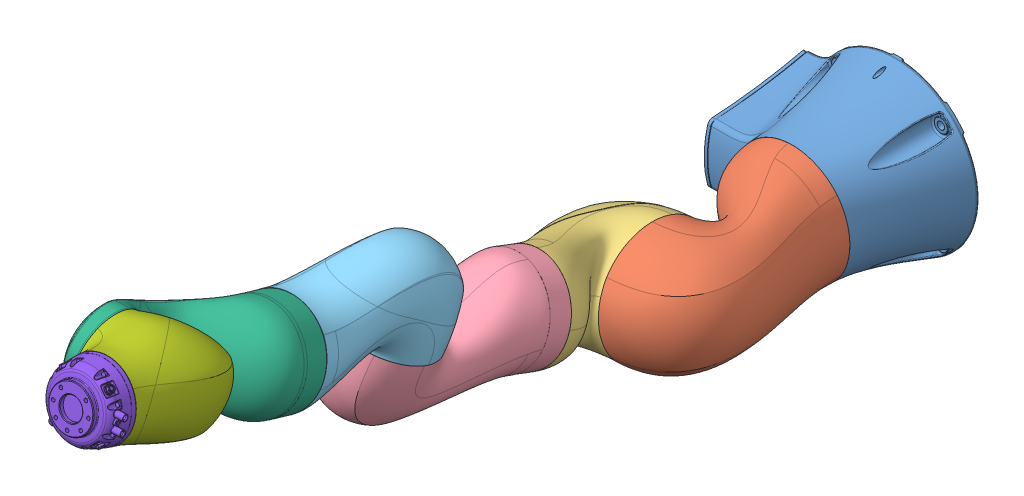
SolidWorks assembly Assembly_1, configuration Default. Lengths in mm.
Overall size (266.54 504.99 1268.37).
8 component instances, 8 part files, 15 mates.
Components (placement in the parent):
- Base_Linkv2-1: Base_Linkv2 [Default] at origin size (257.48 242.95 157.94)
- Link_1v2-1: Link_1v2 [Default] x (-0.064561 0.997914 0) z (0 0 1) size (182.55 209.04 299.35)
- Link_2-1: Link_2 [Default] at (8.0481 -124.3985 22.2717) x (-0.06054 0.935757 -0.34741) z (-0.022429 0.346685 0.937713) size (180.63 205.49 291.74)
- Link_3-1: Link_3 [Default] at (8.0745 -124.8068 22.4232) x (-0.974112 0.203468 -0.098525) z (-0.022429 0.346685 0.937713) size (143.85 187.8 294.72)
- Link_4-1: Link_4 [Default] at (-61.5676 -109.1397 18.4592) x (-0.972074 0.234356 -0.012253) z (0.066856 0.3266 0.942795) size (143.87 187.74 254.27)
- Link_5-1: Link_5 [Default] at (-61.5676 -109.1397 18.4592) x (-0.175544 -0.92632 0.33334) z (0.066856 0.3266 0.942795) size (137.43 170.87 294.55)
- Link_6-1: Link_6 [Default] at (-40.3008 2.9254 -15.504) x (-0.181385 -0.954507 0.236676) z (0.048833 0.231629 0.971578) size (143.46 137.97 168.89)
- Link_8-1: Link_8 [Default] at (-40.3008 2.9254 -15.504) x (0.011265 -0.972804 0.231355) z (0.048833 0.231629 0.971578) size (103.89 109.94 54.9)
Mates (geometry in assembly coordinates):
- Coincident1: coincident anti-aligned: plane of Base_Linkv2-1 through (0 0 147.5) normal (0 0 1); plane of Link_1v2-1 through (0 0 147.5) normal (0 0 -1)
- Concentric1: concentric anti-aligned: cylinder of Base_Linkv2-1 through (0 0 157.5) axis (0 0 1) radius 25; cylinder of Link_1v2-1 through (0 0 157.5) axis (0 0 -1) radius 25
- Coincident2: coincident anti-aligned: plane of Link_1v2-1 through (0 0 335) normal (-0.997914 -0.064561 0); plane of Link_2-1 through (1.8504 -28.6016 282.6387) normal (0.997914 0.064561 0)
- Concentric2: concentric anti-aligned: cylinder of Link_1v2-1 through (0 0 360) axis (-0.997914 -0.064561 0) radius 25; cylinder of Link_2-1 through (0 0 360) axis (0.997914 0.064561 0) radius 25
- Coincident3: coincident anti-aligned: plane of Link_2-1 through (-68.4533 66.7653 551.7624) normal (-0.022429 0.346685 0.937713); plane of Link_3-1 through (-4.5868 70.8972 551.7624) normal (0.022429 -0.346685 -0.937713)
- Concentric3: concentric anti-aligned: cylinder of Link_2-1 through (-4.5868 70.8972 551.7624) axis (-0.022429 0.346685 0.937713) radius 25; cylinder of Link_3-1 through (-4.5868 70.8972 551.7624) axis (0.022429 -0.346685 -0.937713) radius 25
- Coincident4: coincident anti-aligned: plane of Link_3-1 through (-11.7823 135.9936 757.3376) normal (0.224951 0.915647 -0.333147); plane of Link_4-1 through (-11.7823 135.9936 757.3376) normal (-0.224951 -0.915647 0.333147)
- Concentric4: concentric anti-aligned: cylinder of Link_3-1 through (-9.5328 145.1501 754.0061) axis (0.224951 0.915647 -0.333147) radius 25; cylinder of Link_4-1 through (-9.5328 145.1501 754.0061) axis (-0.224951 -0.915647 0.333147) radius 25
- Coincident5: coincident anti-aligned: plane of Link_4-1 through (2.246 202.5995 918.3574) normal (0.066856 0.3266 0.942795); plane of Link_5-1 through (2.246 202.5995 918.3574) normal (-0.066856 -0.3266 -0.942795)
- Concentric5: concentric anti-aligned: cylinder of Link_4-1 through (2.9146 205.8655 927.7853) axis (0.066856 0.3266 0.942795) radius 25; cylinder of Link_5-1 through (2.9146 205.8655 927.7853) axis (-0.066856 -0.3266 -0.942795) radius 25
- Coincident6: coincident anti-aligned: plane of Link_5-1 through (-52.1195 289.5243 1131.2827) normal (0.982199 -0.187787 -0.004597); plane of Link_6-1 through (-52.1195 289.5243 1131.2827) normal (-0.982199 0.187787 0.004597)
- Concentric6: concentric anti-aligned: cylinder of Link_5-1 through (-42.2975 287.6464 1131.2368) axis (0.982199 -0.187787 -0.004597) radius 25; cylinder of Link_6-1 through (-41.61 287.5149 1131.2335) axis (-0.982199 0.187787 0.004597) radius 25
- Coincident7: coincident anti-aligned: plane of Link_6-1 through (20.7939 292.7165 1200.0369) normal (0.048833 0.231629 0.971578); plane of Link_8-1 through (20.7939 292.7165 1200.0369) normal (-0.048833 -0.231629 -0.971578)
- Concentric7: concentric anti-aligned: cylinder of Link_6-1 through (21.2481 294.8707 1209.0726) axis (-0.048833 -0.231629 -0.971578) radius 25; cylinder of Link_8-1 through (20.7939 292.7165 1200.0369) axis (0.048833 0.231629 0.971578) radius 25
- Coincident10: coordinate: point of Base_Linkv2-1
